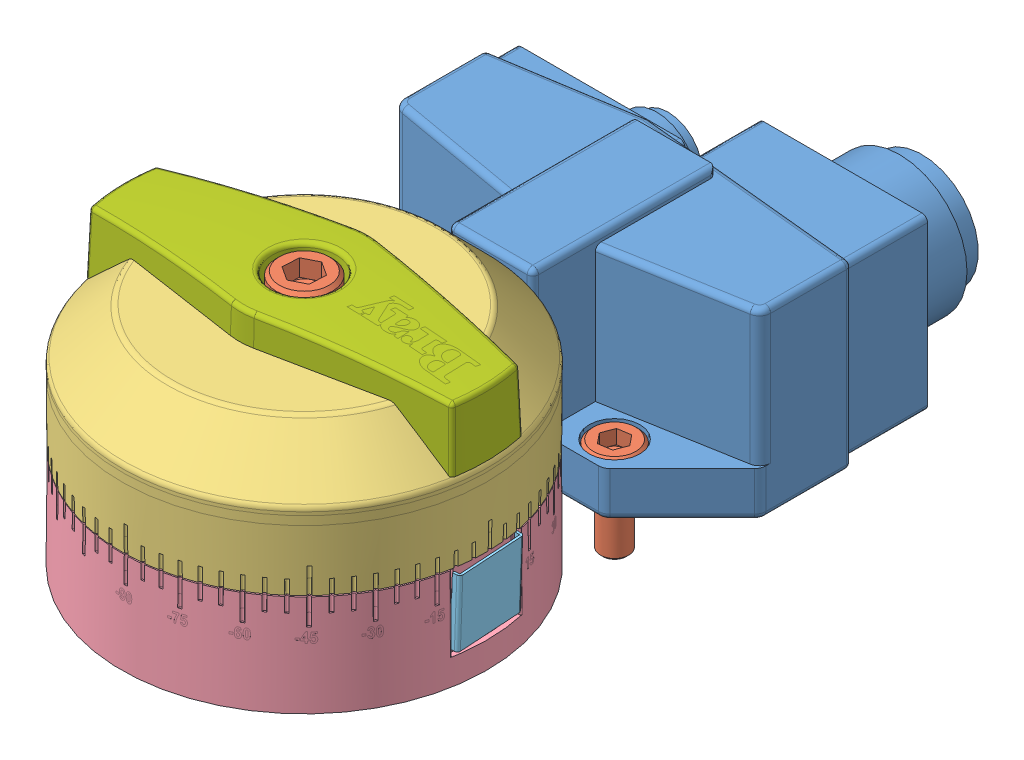
SolidWorks assembly Assem6, configuration Default. Lengths in mm.
Overall size (66.08 55.66 126.03).
10 component instances, 7 part files, 12 mates.
Components (placement in the parent):
- 54-0041-71104-533-1: 54-0041-71104-533 [Default] at (-6.5595 128.9676 -72.9318) size (65.09 33.51 60)
- socket head cap screw_am-1: socket head cap screw_am [B18.3.1M - 5 x 0.8 x 12 Hex SHCS -- 12NHX] at (8.4405 136.9676 -44.4318) x (0 -1 0) z (-0.778168 0 0.628056) size (17 8.5 8.5)
- socket head cap screw_am-2: socket head cap screw_am [B18.3.1M - 5 x 0.8 x 12 Hex SHCS -- 12NHX] at (-21.5823 136.9676 -44.4318) x (0 -1 0) z (-0.778168 0 -0.628056) size (17 8.5 8.5)
- socket head cap screw_am-3: socket head cap screw_am [B18.3.1M - 6 x 1.0 x 30 Hex SHCS -- 30NHX] at (-6.5709 175.3028 -4.4268) x (0 -1 0) z (-0.546944 0 0.837169) size (36 10 10)
- 54-000A-92511-1: 54-000A-92511 [Default] at (-6.5709 148.2716 -4.4268) x (-0.999796 0 0.020182) z (-0.020182 0 -0.999796) size (64.76 21.97 66.01)
- 54-000A-92510-1: 54-000A-92510 [Default] at (-6.5709 130.1868 -4.4268) x (-0.018943 0 -0.999821) z (0.999821 0 -0.018943) size (64.81 35.64 64.77)
- 54-000A-73500-1: 54-000A-73500 [Default] at (25.8784 141.6204 -5.0837) x (-0.060648 0.001457 -0.998158) z (0.997549 -0.034869 -0.060662) size (12.19 11.94 6.35)
- 54-048A-705P0-1: 54-048A-705P0 [Default] at (-6.5709 157.6188 -4.4268) size (44.92 12.57 44.92)
- 54-000A-92512-1: 54-000A-92512 [Default] at (-6.5709 163.9688 -4.4268) x (-0.999645 0 0.026634) z (-0.026634 0 -0.999645) size (64.52 13.44 23.07)
- 54-000A-73500-2: 54-000A-73500 [Default] at (-7.1024 154.2406 -37.0836) x (-0.999979 0 0.00653) z (-0.00653 0 -0.999979) size (12.19 11.94 6.35)
Mates (geometry in assembly coordinates):
- Coincident1: coincident: plane of 54-000A-92511-1 through (-6.3685 163.9688 5.6042) normal (0 1 0); plane of 54-000A-92512-1 through (-6.3737 163.9688 2.9747) normal (0 -1 0)
- Coincident2: coincident: plane of socket head cap screw_am-3 through (-2.3851 169.3028 -1.6921) normal (0 -1 0); circle of 54-000A-92512-1
- Parallel1: parallel: plane of 54-000A-92510-1 through (23.8528 134.835 -5.0032) normal (0.034893 0.999391 -0.000661); plane of 54-000A-73500-1 through (26.0398 135.6461 1.005) normal (-0.034893 -0.999391 0.000661)
- Tangent1: tangent: face of 54-000A-92511-1; line of 54-000A-73500-2 through (-1.003 148.2716 -36.59) axis (0 1 0)
- Coincident3: coincident: plane of 54-000A-92511-1 through (-6.3169 160.7938 8.1564) normal (0 -1 0); plane of 54-000A-92510-1 through (-6.8139 160.7938 -17.2515) normal (0 1 0)
- Coincident4: coincident: plane of 54-000A-92511-1 through (-5.971 148.2716 25.2946) normal (0 -1 0); plane of 54-000A-73500-2 through (-1.0065 148.2716 -37.1234) normal (0 -1 0)
- Coincident5: coincident: plane of 54-000A-92510-1 through (-6.9775 157.6188 -25.8859) normal (0 -1 0); plane of 54-048A-705P0-1 through (-6.5709 157.6188 -4.4268) normal (0 1 0)
- Coincident6: coincident: plane of 54-0041-71104-533-1 through (8.4405 131.9676 -44.4318) normal (0 1 0); plane of socket head cap screw_am-1 through (11.1097 131.9676 -41.1246) normal (0 -1 0)
- Concentric1: concentric: cylinder of 54-000A-92510-1 through (-6.5709 120.853 -4.4268) axis (0 1 0) radius 3.3; cylinder of 54-000A-92512-1 through (-6.5709 163.9688 -4.4268) axis (0 -1 0) radius 3.3
- Concentric2: concentric: cylinder of socket head cap screw_am-3 through (-6.5709 207.0528 -4.4268) axis (0 1 0) radius 3; cylinder of 54-000A-92512-1 through (-6.5709 163.9688 -4.4268) axis (0 -1 0) radius 3.3
- Concentric3: concentric: cylinder of 54-000A-92511-1 through (-6.5709 151.46 -4.4268) axis (0 1 0) radius 3.3; cylinder of 54-000A-92512-1 through (-6.5709 163.9688 -4.4268) axis (0 -1 0) radius 3.3
- Concentric4: concentric: cylinder of 54-0041-71104-533-1 through (8.4405 125.0501 -44.4318) axis (0 1 0) radius 4.5; cylinder of socket head cap screw_am-1 through (8.4405 168.7176 -44.4318) axis (0 1 0) radius 4.25
